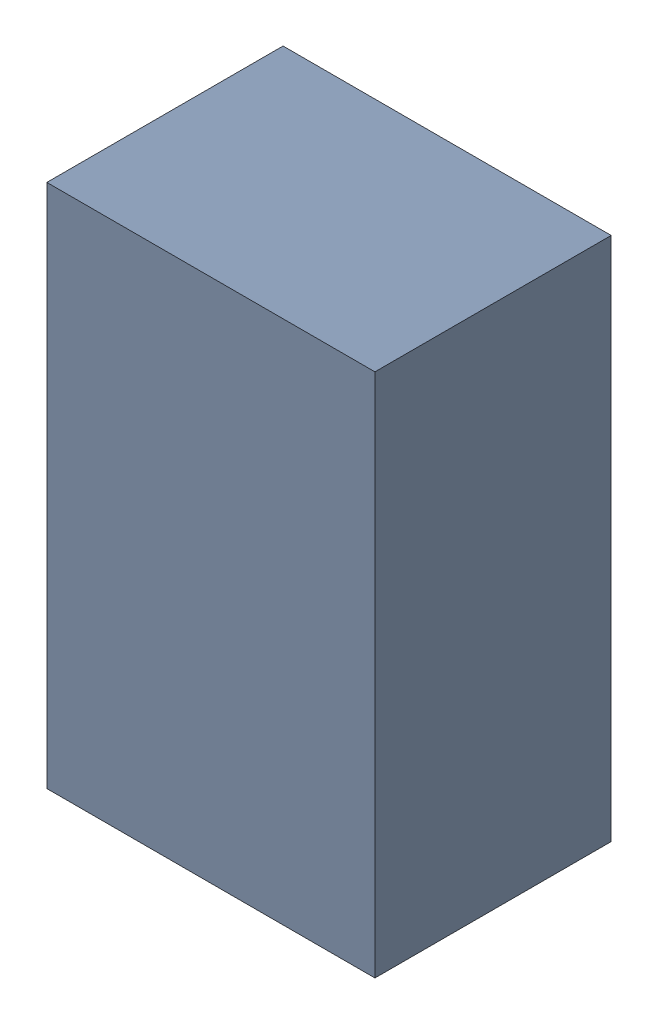
SolidWorks assembly U10, configuration Default. Lengths in mm.
Overall size (1.25 2 0.9).
2 component instances, 1 part files, 0 mates.
Components (placement in the parent):
- 870945920-1: 870945920 [Default] at (16.6362 34.3856 -2.6006) size (1.25 2 0.9)
  - Extruded_8-1: Extruded_8 [Default] at origin size (1.25 2 0.9)
